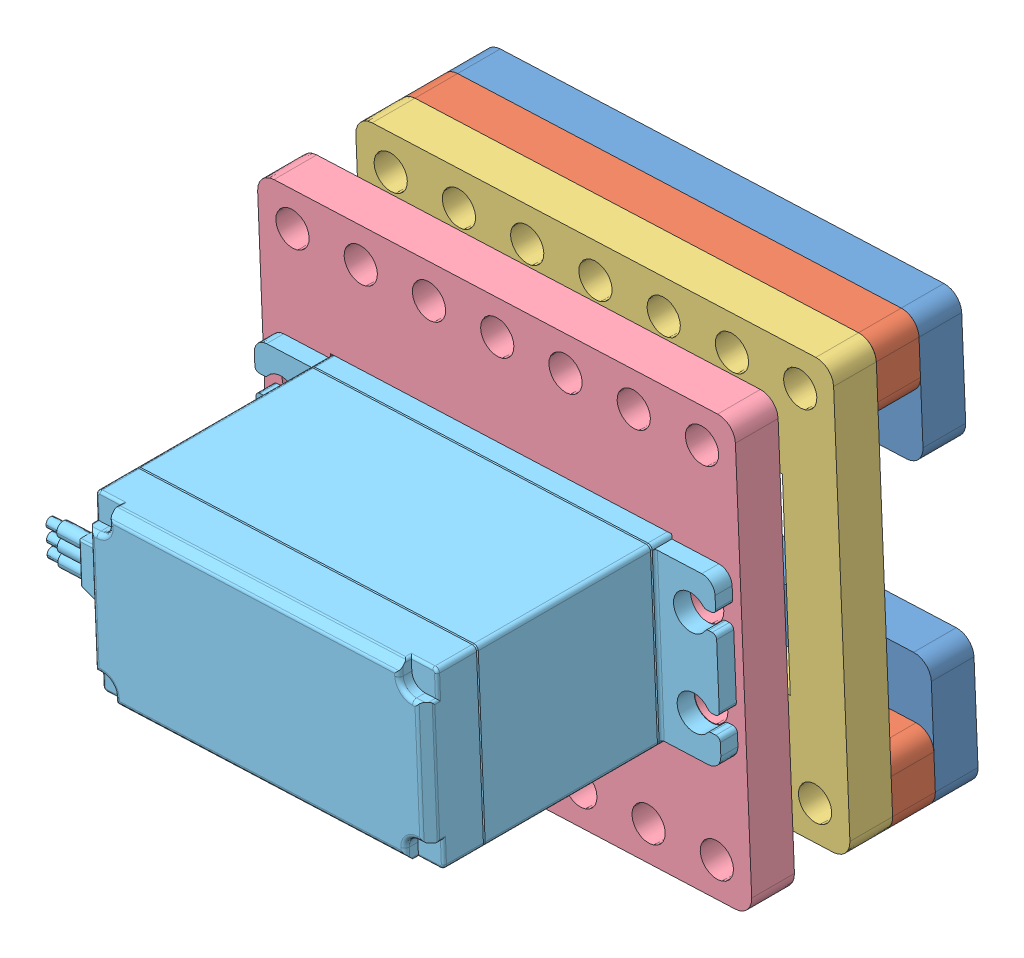
SolidWorks assembly assemblage ascenseur, configuration Default. Lengths in mm.
Overall size (58.03 51.54 55.5).
10 component instances, 8 part files, 27 mates.
Components (placement in the parent):
- 3mm support servo 5-1: 3mm support servo 5 [Default] at (55.3297 16.1146 111.995) x (-0.99911 -0.042175 0) z (0.042175 -0.99911 0) size (56 5 15)
- support servo 2-1: support servo 2 [Default] at (111.2799 18.4764 116.995) x (-0.99911 -0.042175 0) z (0.042175 -0.99911 0) size (56 5 8)
- X7 support servo 3-1: X7 support servo 3 [Default] at (55.3297 16.1146 121.995) x (-0.99911 -0.042175 0) z (0.042175 -0.99911 0) size (56 5 49.22)
- support servo 4-1: support servo 4 [Default] at (35.4252 -33.9894 133.495) x (0.99911 0.042175 0) z (-0.042175 0.99911 0) size (56 5 49.22)
- MG995.step-1: MG995.step [Default] at (84.3427 -7.2923 162.495) x (-0.99911 -0.042175 0) z (0 0 -1) size (55.5 20 44.5)
- 3mm support servo 5-2: 3mm support servo 5 [Default] at (57.4056 -33.0616 106.995) x (-0.99911 -0.042175 0) z (-0.042175 0.99911 0) size (56 5 15)
- new attach-1: new attach [Default] at (74.3516 -7.7141 116.995) x (0.990938 -0.134316 0) z (0 0 1) size (21 21 5.5)
- new attach 2-1: new attach 2 [Default] at (74.3516 -7.7141 111.995) x (-0.134316 -0.990938 0) z (0 0 1) size (24.86 25 5)
- support servo 2-3: support servo 2 [Default] at (57.4056 -33.0616 116.995) x (0.99911 0.042175 0) z (-0.042175 0.99911 0) size (56 5 8)
- NEW HORN-1: NEW HORN [Default] at (84.3427 -7.2923 117.995) x (-0.99911 -0.042175 0) z (0 0 -1) size (9.55 9.02 10)
Mates (geometry in assembly coordinates):
- Concentric2: concentric anti-aligned: cylinder of support servo 4-1 through (60.575 -13.3001 133.495) axis (0 0 -1) radius 1.95; cylinder of MG995.step-1 through (60.575 -13.3001 133.495) axis (0 0 1) radius 2
- Coincident3: coincident anti-aligned: plane of support servo 4-1 through (131.3465 17.3217 133.495) normal (0 0 1); plane of MG995.step-1 through (84.3427 -7.2923 133.495) normal (0 0 -1)
- Concentric12: concentric aligned: cylinder of MG995.step-1 through (74.3516 -7.7141 122.995) axis (0 0 1) radius 2; cylinder of new attach-1 through (74.3516 -7.7141 117.995) axis (0 0 1) radius 2.75
- Coincident30: coincident anti-aligned: plane of MG995.step-1 through (74.3516 -7.7141 117.995) normal (0 0 -1); plane of new attach-1 through (74.3516 -7.7141 117.995) normal (0 0 1)
- Concentric13: concentric aligned: cylinder of new attach-1 through (74.3516 -7.7141 120.495) axis (0 0 -1) radius 1.6; cylinder of new attach 2-1 through (74.3516 -7.7141 116.995) axis (0 0 -1) radius 1.6
- Coincident34: coincident anti-aligned: plane of new attach-1 through (74.3516 -7.7141 116.995) normal (0 0 -1); plane of new attach 2-1 through (74.3516 -7.7141 116.995) normal (0 0 1)
- Concentric15: concentric anti-aligned: cylinder of new attach-1 through (82.0204 -6.2307 115.495) axis (0 0 1) radius 1; cylinder of new attach 2-1 through (82.0204 -6.2307 116.995) axis (0 0 -1) radius 1
- Coincident44: coincident aligned: plane of support servo 4-1 through (113.3558 -30.6998 138.495) normal (0.99911 0.042175 0); plane of support servo 2-3 through (113.2714 -28.7015 111.995) normal (0.99911 0.042175 0)
- Coincident45: coincident aligned: plane of support servo 2-1 through (111.3643 16.4782 111.995) normal (0.99911 0.042175 0); plane of support servo 4-1 through (113.3558 -30.6998 138.495) normal (0.99911 0.042175 0)
- Coincident46: coincident aligned: plane of support servo 2-1 through (111.3643 16.4782 111.995) normal (0.99911 0.042175 0); plane of support servo 3-1 through (111.3643 16.4782 116.995) normal (0.99911 0.042175 0)
- Coincident48: coincident anti-aligned: plane of support servo 2-1 through (57.581 10.2043 116.995) normal (0 0 1); plane of support servo 3-1 through (59.3194 -30.979 116.995) normal (0 0 -1)
- Coincident49: coincident aligned: plane of support servo 2-1 through (109.2817 18.3921 111.995) normal (-0.042175 0.99911 0); plane of support servo 3-1 through (109.2817 18.3921 116.995) normal (-0.042175 0.99911 0)
- Coincident50: coincident anti-aligned: plane of support servo 4-1 through (63.9388 1.855 133.495) normal (0.042175 -0.99911 0); plane of MG995.step-1 through (103.9032 3.5423 126.495) normal (-0.042175 0.99911 0)
- Coincident51: coincident anti-aligned: plane of 3mm support servo 5-1 through (57.8762 3.2106 111.995) normal (0 0 1); plane of support servo 2-1 through (57.581 10.2043 111.995) normal (0 0 -1)
- Coincident52: coincident aligned: plane of 3mm support servo 5-1 through (109.2817 18.3921 106.995) normal (-0.042175 0.99911 0); plane of support servo 2-1 through (109.2817 18.3921 111.995) normal (-0.042175 0.99911 0)
- Coincident53: coincident aligned: plane of 3mm support servo 5-1 through (55.4141 14.1164 106.995) normal (-0.99911 -0.042175 0); plane of support servo 2-1 through (55.4141 14.1164 111.995) normal (-0.99911 -0.042175 0)
- Coincident54: coincident anti-aligned: plane of 3mm support servo 5-2 through (58.8555 -19.9888 111.995) normal (0 0 1); plane of support servo 2-3 through (111.1045 -24.7895 111.995) normal (0 0 -1)
- Coincident55: coincident aligned: plane of 3mm support servo 5-2 through (111.3575 -30.7841 111.995) normal (0.042175 -0.99911 0); plane of support servo 2-3 through (59.4038 -32.9772 111.995) normal (0.042175 -0.99911 0)
- Coincident56: coincident aligned: plane of 3mm support servo 5-2 through (57.3212 -31.0633 111.995) normal (-0.99911 -0.042175 0); plane of support servo 2-3 through (57.3212 -31.0633 111.995) normal (-0.99911 -0.042175 0)
- Coincident57: coincident aligned: plane of new attach 2-1 through (74.3516 -7.7141 111.995) normal (0 0 -1); plane of support servo 2-3 through (111.1045 -24.7895 111.995) normal (0 0 -1)
- Coincident58: coincident anti-aligned: plane of support servo 3-1 through (59.3194 -30.979 116.995) normal (0 0 -1); plane of support servo 2-3 through (111.1045 -24.7895 116.995) normal (0 0 1)
- Coincident59: coincident aligned: plane of support servo 3-1 through (111.3575 -30.7841 116.995) normal (0.042175 -0.99911 0); plane of support servo 2-3 through (59.4038 -32.9772 111.995) normal (0.042175 -0.99911 0)
- Coincident60: coincident aligned: plane of support servo 4-1 through (37.4234 -33.9051 128.495) normal (0.042175 -0.99911 0); plane of support servo 2-3 through (59.4038 -32.9772 111.995) normal (0.042175 -0.99911 0)
- InPlace1: in place: plane of MG995.step-1 through (74.3516 -7.7141 117.995) normal (0 0 -1); plane of ? through (0 0 117.995) normal (0 0 -1); moOrthogonalPlaneRef_w of MG995.step-1 through (74.3516 -7.7141 117.995) normal (0 0 -1); plane of ? through (0 0 117.995) normal (0 1 0); plane of MG995.step-1 through (74.3516 -7.7141 117.995) normal (0 0 -1); plane of ? through (0 0 117.995) normal (-1 0 0); plane of MG995.step-1 through (74.3516 -7.7141 117.995) normal (0 0 -1); unknown of NEW HORN-1
- Coincident61: coincident aligned: plane of MG995.step-1; plane of NEW HORN-1
- Coincident62: coincident aligned: moOrthogonalPlaneRef_w of MG995.step-1 through (84.3427 -7.2923 117.995) normal (-0.042175 0.99911 0); plane of NEW HORN-1 through (84.3427 -7.2923 117.995) normal (-0.042175 0.99911 0)
- Coincident63: coincident anti-aligned: moOrthogonalPlaneRef_w of MG995.step-1 through (84.3427 -7.2923 117.995) normal (0.99911 0.042175 0); plane of NEW HORN-1 through (84.3427 -7.2923 117.995) normal (-0.99911 -0.042175 0)
